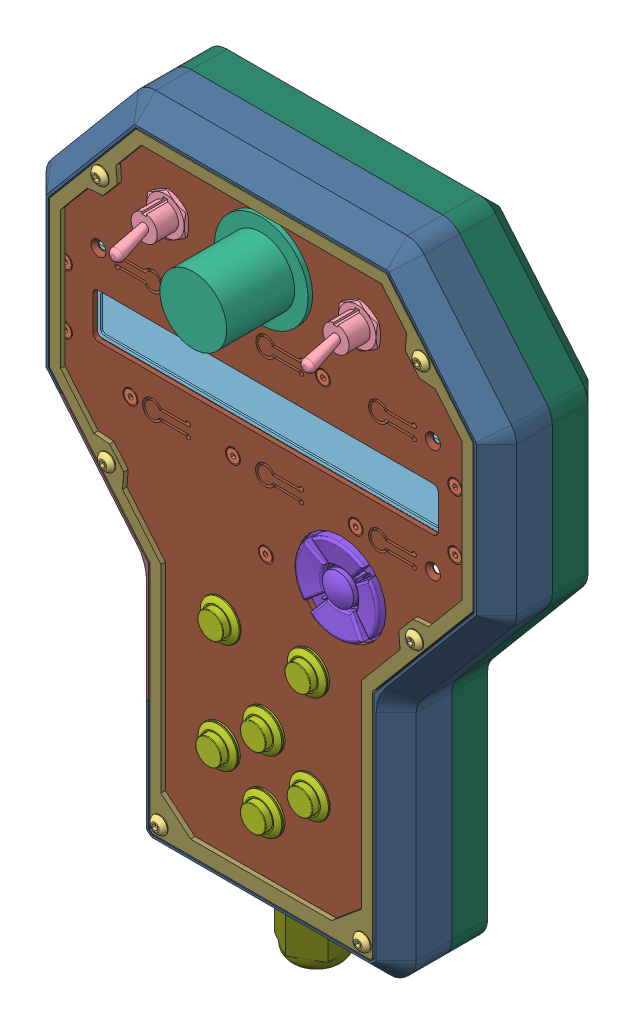
SolidWorks assembly Montagem, configuration Valor predeterminado. Lengths in mm.
Overall size (211 315 80.5).
60 component instances, 19 part files, 130 mates.
Components (placement in the parent):
- hex nut style 1 gradeab_din-3: hex nut style 1 gradeab_din [Hexagon Nut ISO 4032 - M4 - W - N] at (-95.2029 -0.5297 -15.05) x (-0.766044 -0.642788 0) z (0 0 1) size (7 8.08 3.2)
- hex nut style 1 gradeab_din-4: hex nut style 1 gradeab_din [Hexagon Nut ISO 4032 - M4 - W - N] at (42.9071 -0.5197 -15.05) x (0.766044 -0.642788 0) z (0 0 1) size (7 8.08 3.2)
- hex nut style 1 gradeab_din-5: hex nut style 1 gradeab_din [Hexagon Nut ISO 4032 - M4 - W - N] at (-69.6429 -49.9305 2.95) x (0.5 0.866025 0) z (0 0 1) size (7 8.08 3.2)
- hex nut style 1 gradeab_din-6: hex nut style 1 gradeab_din [Hexagon Nut ISO 4032 - M4 - W - N] at (33.6932 120.5695 2.95) x (0.766044 0.642788 0) z (0 0 1) size (7 8.08 3.2)
- hex nut style 1 gradeab_din-7: hex nut style 1 gradeab_din [Hexagon Nut ISO 4032 - M4 - W - N] at (17.3571 -99.7712 2.95) size (7 8.08 3.2)
- hex nut style 1 gradeab_din-8: hex nut style 1 gradeab_din [Hexagon Nut ISO 4032 - M4 - W - N] at (-85.979 120.5695 2.95) x (0.766044 -0.642788 0) z (0 0 1) size (7 8.08 3.2)
- hex nut style 1 gradeab_din-9: hex nut style 1 gradeab_din [Hexagon Nut ISO 4032 - M4 - W - N] at (-69.6429 -99.7712 2.95) size (7 8.08 3.2)
- hex nut style 1 gradeab_din-10: hex nut style 1 gradeab_din [Hexagon Nut ISO 4032 - M4 - W - N] at (45.8324 109.2141 -7.45) x (0.939693 -0.34202 0) z (0 0 -1) size (7 8.08 3.2)
- hex nut style 1 gradeab_din-11: hex nut style 1 gradeab_din [Hexagon Nut ISO 4032 - M4 - W - N] at (-71.6429 -129.7045 -7.45) x (0.5 0.866025 0) z (0 0 -1) size (7 8.08 3.2)
- hex nut style 1 gradeab_din-12: hex nut style 1 gradeab_din [Hexagon Nut ISO 4032 - M4 - W - N] at (19.3571 -129.7045 -7.45) x (1 0 0) z (0 0 -1) size (7 8.08 3.2)
- hex nut style 1 gradeab_din-13: hex nut style 1 gradeab_din [Hexagon Nut ISO 4032 - M4 - W - N] at (-98.1182 109.2141 -7.45) x (-0.939693 -0.34202 0) z (0 0 -1) size (7 8.08 3.2)
- socket countersunk head screw_din-8: socket countersunk head screw_din [DIN 7991 - M3 x 16 --- 12.8C] at (58.8311 39.2309 11.75) x (0 0 -1) z (1 0 0) size (16 5.7 5.7)
- socket countersunk head screw_din-9: socket countersunk head screw_din [DIN 7991 - M3 x 16 --- 12.8C] at (-86.7826 27.8805 11.75) x (0 0 -1) z (-0.923728 -0.383049 0) size (16 5.7 5.7)
- socket countersunk head screw_din-10: socket countersunk head screw_din [DIN 7991 - M3 x 16 --- 12.8C] at (-116.1689 65.7309 11.75) x (0 0 -1) z (-0.923728 -0.383049 0) size (16 5.7 5.7)
- socket countersunk head screw_din-11: socket countersunk head screw_din [DIN 7991 - M3 x 16 --- 12.8C] at (-0.483 78.4595 11.75) x (0 0 -1) z (0.923728 0.383049 0) size (16 5.7 5.7)
- socket countersunk head screw_din-12: socket countersunk head screw_din [DIN 7991 - M3 x 16 --- 12.8C] at (-116.1689 39.2309 11.75) x (0 0 -1) z (-0.923728 -0.383049 0) size (16 5.7 5.7)
- socket countersunk head screw_din-13: socket countersunk head screw_din [DIN 7991 - M3 x 16 --- 12.8C] at (-52.483 78.4595 11.75) x (0 0 -1) z (0.923728 0.383049 0) size (16 5.7 5.7)
- socket countersunk head screw_din-14: socket countersunk head screw_din [DIN 7991 - M3 x 16 --- 12.8C] at (58.8311 65.7309 11.75) x (0 0 -1) z (0.923728 0.383049 0) size (16 5.7 5.7)
- socket countersunk head screw_din-15: socket countersunk head screw_din [DIN 7991 - M3 x 16 --- 12.8C] at (14.2174 27.8805 11.75) x (0 0 -1) z (1 0 0) size (16 5.7 5.7)
- socket countersunk head screw_din-16: socket countersunk head screw_din [DIN 7991 - M3 x 16 --- 12.8C] at (-40.7826 27.8805 11.75) x (0 0 -1) z (0.277326 0.960776 0) size (16 5.7 5.7)
- socket countersunk head screw_din-17: socket countersunk head screw_din [DIN 7991 - M3 x 16 --- 12.8C] at (-26.2001 -3.0051 11.75) x (0 0 -1) z (-0.006263 -0.99998 0) size (16 5.7 5.7)
- hex nut style 1 gradeab_din-15: hex nut style 1 gradeab_din [Hexagon Nut ISO 4032 - M3 - W - N] at (-40.7826 27.8805 0.1586) x (0.012479 -0.999922 0) z (0 0 -1) size (5.5 6.35 2.4)
- hex nut style 1 gradeab_din-16: hex nut style 1 gradeab_din [Hexagon Nut ISO 4032 - M3 - W - N] at (-52.483 78.4595 0.1586) x (0.904381 -0.426726 0) z (0 0 -1) size (5.5 6.35 2.4)
- hex nut style 1 gradeab_din-17: hex nut style 1 gradeab_din [Hexagon Nut ISO 4032 - M3 - W - N] at (-0.483 78.4595 0.1586) x (-0.993944 0.109886 0) z (0 0 -1) size (5.5 6.35 2.4)
- hex nut style 1 gradeab_din-18: hex nut style 1 gradeab_din [Hexagon Nut ISO 4032 - M3 - W - N] at (14.2174 27.8805 0.1586) x (-0.816279 -0.577658 0) z (0 0 -1) size (5.5 6.35 2.4)
- hex nut style 1 gradeab_din-19: hex nut style 1 gradeab_din [Hexagon Nut ISO 4032 - M3 - W - N] at (-86.7826 27.8805 0.1586) x (-0.525463 -0.850817 0) z (0 0 -1) size (5.5 6.35 2.4)
- hex nut style 1 gradeab_din-20: hex nut style 1 gradeab_din [Hexagon Nut ISO 4032 - M3 - W - N] at (-116.1689 65.7309 -3.318) x (0.297598 -0.954691 0) z (0 0 -1) size (5.5 6.35 2.4)
- hex nut style 1 gradeab_din-21: hex nut style 1 gradeab_din [Hexagon Nut ISO 4032 - M3 - W - N] at (-116.1689 39.2309 -3.318) x (0.646896 0.762578 0) z (0 0 -1) size (5.5 6.35 2.4)
- hex nut style 1 gradeab_din-22: hex nut style 1 gradeab_din [Hexagon Nut ISO 4032 - M3 - W - N] at (58.8311 65.7309 -3.318) x (0.923728 0.383049 0) z (0 0 -1) size (5.5 6.35 2.4)
- hex nut style 1 gradeab_din-23: hex nut style 1 gradeab_din [Hexagon Nut ISO 4032 - M3 - W - N] at (58.8311 39.2309 -3.318) x (0.923728 0.383049 0) z (0 0 -1) size (5.5 6.35 2.4)
- hex nut style 1 gradeab_din-24: hex nut style 1 gradeab_din [Hexagon Nut ISO 4032 - M3 - W - N] at (-26.2001 -3.0051 0.1586) x (0.05846 -0.99829 0) z (0 0 -1) size (5.5 6.35 2.4)
- socket button head screw_iso-9: socket button head screw_iso [ISO 7380 - M4 x 16 --- 16N] at (45.8295 109.2085 15.95) x (0 0 -1) z (1 0 0) size (18.2 7.6 7.6)
- socket button head screw_iso-10: socket button head screw_iso [ISO 7380 - M4 x 16 --- 16N] at (-98.1153 109.2085 15.95) x (0 0 -1) z (0.767389 -0.641182 0) size (18.2 7.6 7.6)
- socket button head screw_iso-11: socket button head screw_iso [ISO 7380 - M4 x 16 --- 16N] at (-71.6429 -129.7005 15.95) x (0 0 -1) z (1 0 0) size (18.2 7.6 7.6)
- socket button head screw_iso-12: socket button head screw_iso [ISO 7380 - M4 x 16 --- 16N] at (19.3571 -129.7005 15.95) x (0 0 -1) z (1 0 0) size (18.2 7.6 7.6)
- socket button head screw_iso-14: socket button head screw_iso [ISO 7380 - M4 x 16 --- 16N] at (-95.1957 -0.5218 15.95) x (0 0 -1) z (1 0 0) size (18.2 7.6 7.6)
- socket button head screw_iso-13: socket button head screw_iso [ISO 7380 - M4 x 16 --- 16N] at (42.9099 -0.5218 15.95) x (0 0 -1) z (1 0 0) size (18.2 7.6 7.6)
- BCV3 112 103 - Controle chave geral-1: BCV3 112 103 - Controle chave geral [Default] at (-69.1429 108.0695 2.25) size (17 29 51.5)
- BCV3 112 103 - Controle chave geral-2: BCV3 112 103 - Controle chave geral [Default] at (16.8571 108.0695 2.25) size (17 29 51.5)
- LCD Display 4002-1: LCD Display 4002 [Valor predeterminado] at (-28.6689 52.4809 -3.8644) size (182 33.5 13.65)
- Botão emergencia-1: Botão emergencia [Valor predeterminado] at (-26.1429 108.0695 -28.25) x (0.351629 -0.93614 0) z (-0.93614 -0.351629 0) size (42 72.5 42)
- AV16HA-1: AV16HA [Valor predeterminado] at (-26.1429 -102.8813 -2.3) x (-0.899754 -0.436397 0) z (-0.436397 0.899754 0) size (21.5 29.33 19.15)
- AV16HA-2: AV16HA [Valor predeterminado] at (-46.1429 -38.2603 -3.25) x (0.225316 -0.974286 0) z (-0.974286 -0.225316 0) size (21.5 29.33 19.15)
- AV16HA-3: AV16HA [Valor predeterminado] at (-26.1429 -70.8635 -2.3) x (0.278036 0.960571 0) z (0.960571 -0.278036 0) size (21.5 29.33 19.15)
- AV16HA-4: AV16HA [Valor predeterminado] at (-6.1429 -86.846 -3.25) x (0.980248 0.197772 0) z (0.197772 -0.980248 0) size (21.5 29.33 19.15)
- AV16HA-5: AV16HA [Valor predeterminado] at (-46.1429 -86.846 -2.3) x (0.999797 0.02015 0) z (0.02015 -0.999797 0) size (21.5 29.33 19.15)
- AV16HA-6: AV16HA [Valor predeterminado] at (-6.1429 -38.2603 -2.3) x (-0.950101 -0.311942 0) z (-0.311942 0.950101 0) size (21.5 29.33 19.15)
- PCB-2: PCB [Valor predeterminado] at (-91.4326 8.3805 4.15) size (130.25 57.71 27.35)
- Teclas_Superiores-2: Teclas_Superiores [Valor predeterminado] at (-91.433 46.0455 4.15) size (130.25 12.75 19.2)
- TEC001 - Moldura -1: TEC001 - Moldura  [Valor predeterminado] at (-26.1429 -144.6278 -11.25) size (211 291 25)
- TEC002 - Placa Superior-1: TEC002 - Placa Superior [Valor predeterminado] at (-25.2999 1.2599 9.75) size (190 270 2)
- TEC003 - Moldura alumínio-1: TEC003 - Moldura alumínio [Valor predeterminado] at (-26.4426 -0.0902 11.75) size (190 270 2)
- TEC004 - Moldura Borracha-1: TEC004 - Moldura Borracha [Valor predeterminado] at (-26.6429 -144.6278 -11.25) size (64.1 110 25)
- TEC005 - Moldura Borracha Inferior-1: TEC005 - Moldura Borracha Inferior [Valor predeterminado] at (-26.6429 -144.6278 -11.25) size (64.1 110 25)
- TEC006 - Placa Inferior-1: TEC006 - Placa Inferior [Valor predeterminado] at (-25.2999 1.2599 -34.75) size (190 270 1.5) (hidden)
- TEC007 - Moldura  Inferior-1: TEC007 - Moldura  Inferior [Valor predeterminado] at (-26.1429 -144.6278 -11.25) size (211 291 25)
- Prensa cabo-1: Prensa cabo [Valor predeterminado] at (-26.1429 -154.9305 -11.0191) x (0.5 0 0.866025) z (0 -1 0) size (27.2 31.41 34)
- TEC008 - Pino-1: TEC008 - Pino [Valor predeterminado] at (-127.6429 32.3003 0.75) x (0.794362 -0.607445 0) z (0.607445 0.794362 0) size (4 25 4)
- TEC008 - Pino-2: TEC008 - Pino [Valor predeterminado] at (-80.1429 -114.1997 -24.25) x (0.610836 -0.791757 0) z (-0.791757 -0.610836 0) size (4 25 4)
- placa inferior-1: placa inferior [Valor predeterminado] at (-18.5596 4.7575 -324.8091) x (-1 0 0) z (0 0 -1) size (146 57.5 4) (hidden)
Mates (geometry in assembly coordinates):
- Coincidente2: coincident: plane of TEC001 - Moldura -1 through (-26.1429 -144.6278 13.75) normal (0 0 1); plane of Botão emergencia-1 through (-33.5271 127.7285 13.75) normal (0 0 1)
- Coincidente24: coincident: plane of TEC001 - Moldura -1 through (-26.1429 -144.6278 9.75) normal (0 0 1); plane of TEC002 - Placa Superior-1 through (-25.2999 1.2599 9.75) normal (0 0 -1)
- Coincidente35: coincident: plane of TEC001 - Moldura -1 through (-49.8107 -84.1997 -11.25) normal (0 1 0); plane of TEC004 - Moldura Borracha-1 through (-50.3107 -84.1997 -11.25) normal (0 -1 0)
- Coincidente36: coincident: plane of TEC002 - Placa Superior-1 through (-25.2999 1.2599 9.75) normal (0 0 -1); plane of TEC004 - Moldura Borracha-1 through (-26.6429 -144.6278 9.75) normal (0 0 1)
- Concêntrico6: concentric: cylinder of AV16HA-1 through (-26.1429 -102.8813 -2.3) axis (0 0 1) radius 7.95; cylinder of TEC002 - Placa Superior-1 through (-26.1429 -102.8813 9.749) axis (0 0 1) radius 8
- Tangente1: tangent: plane of TEC002 - Placa Superior-1 through (-25.2999 1.2599 11.75) normal (0 0 1); face of AV16HA-1
- Concêntrico9: concentric: cylinder of AV16HA-4 through (-6.1429 -86.846 -3.25) axis (0 0 1) radius 7.95; cylinder of TEC002 - Placa Superior-1 through (-6.1429 -86.846 9.749) axis (0 0 1) radius 8
- Concêntrico10: concentric: cylinder of AV16HA-3 through (-26.1429 -70.8635 -2.3) axis (0 0 1) radius 7.95; cylinder of TEC002 - Placa Superior-1 through (-26.1429 -70.8635 9.749) axis (0 0 1) radius 8
- Tangente2: tangent: plane of TEC002 - Placa Superior-1 through (-25.2999 1.2599 11.75) normal (0 0 1); face of AV16HA-5
- Tangente3: tangent: plane of TEC002 - Placa Superior-1 through (-25.2999 1.2599 11.75) normal (0 0 1); face of AV16HA-6
- Tangente4: tangent: plane of TEC002 - Placa Superior-1 through (-25.2999 1.2599 11.75) normal (0 0 1); face of AV16HA-4
- Tangente5: tangent: plane of TEC002 - Placa Superior-1 through (-25.2999 1.2599 11.75) normal (0 0 1); face of AV16HA-2
- Tangente6: tangent: plane of TEC002 - Placa Superior-1 through (-25.2999 1.2599 11.75) normal (0 0 1); face of AV16HA-3
- Concêntrico12: concentric: cylinder of Botão emergencia-1 through (-26.1429 108.0695 -50.7451) axis (0 0 -1) radius 15; cylinder of TEC002 - Placa Superior-1 through (-26.1429 108.0695 9.749) axis (0 0 1) radius 11.25
- Concêntrico13: concentric: cylinder of BCV3 112 103 - Controle chave geral-1 through (-69.1429 108.0695 23.25) axis (0 0 -1) radius 5.85; cylinder of TEC002 - Placa Superior-1 through (-69.1429 108.0695 9.749) axis (0 0 1) radius 6
- Concêntrico15: concentric: cylinder of BCV3 112 103 - Controle chave geral-2 through (16.8571 108.0695 23.25) axis (0 0 -1) radius 5.85; cylinder of TEC002 - Placa Superior-1 through (16.8571 108.0695 9.749) axis (0 0 1) radius 6
- Coincidente38: coincident: plane of BCV3 112 103 - Controle chave geral-1 through (-69.1429 117.8845 11.75) normal (0 0 -1); plane of TEC002 - Placa Superior-1 through (-25.2999 1.2599 11.75) normal (0 0 1)
- Coincidente39: coincident: plane of BCV3 112 103 - Controle chave geral-2 through (16.8571 117.8845 11.75) normal (0 0 -1); plane of TEC002 - Placa Superior-1 through (-25.2999 1.2599 11.75) normal (0 0 1)
- Coincidente40: coincident: plane of TEC001 - Moldura -1 through (-39.9429 -142.4305 -3.2826) normal (0.5 0 -0.866025); plane of Prensa cabo-1 through (-39.7429 -142.4305 -3.1671) normal (-0.5 0 0.866025)
- Coincidente41: coincident: plane of TEC001 - Moldura -1 through (-26.1429 -142.4305 4.6849) normal (-0.5 0 -0.866025); plane of Prensa cabo-1 through (-26.1429 -142.4305 4.6849) normal (0.5 0 0.866025)
- Coincidente42: coincident: plane of TEC001 - Moldura -1 through (-26.1429 -142.4305 -11.25) normal (0 1 0); plane of Prensa cabo-1 through (-26.1429 -142.4305 -11.0191) normal (0 -1 0)
- Distância9: distance = 0.5 mm: plane of TEC002 - Placa Superior-1 through (-121.1429 88.7866 11.75) normal (-1 0 0); plane of TEC001 - Moldura -1 through (-121.6429 88.9571 9.75) normal (1 0 0)
- Distância10: distance = 0.5 mm: plane of TEC002 - Placa Superior-1 through (30.0211 135.0695 11.75) normal (0 1 0); plane of TEC001 - Moldura -1 through (30.2446 135.5695 9.75) normal (0 -1 0)
- Coincidente49: coincident: plane of TEC002 - Placa Superior-1 through (-25.2999 1.2599 11.75) normal (0 0 1); plane of TEC003 - Moldura alumínio-1 through (-26.4426 -0.0902 11.75) normal (0 0 -1)
- Coincidente50: coincident: plane of TEC002 - Placa Superior-1 through (-121.1429 88.7866 11.75) normal (-1 0 0); plane of TEC003 - Moldura alumínio-1 through (-121.1429 88.7866 13.75) normal (-1 0 0)
- Coincidente51: coincident: plane of TEC002 - Placa Superior-1 through (-74.8228 -134.9305 11.75) normal (0 -1 0); plane of TEC003 - Moldura alumínio-1 through (-74.8228 -134.9305 13.75) normal (0 -1 0)
- Coincidente52: coincident: plane of TEC001 - Moldura -1 through (-86.6429 -144.6278 13.75) normal (-1 0 0); plane of TEC004 - Moldura Borracha-1 through (-86.6429 -144.6278 13.75) normal (-1 0 0)
- Coincidente53: coincident: plane of TEC001 - Moldura -1 through (-26.1429 145.5695 13.75) normal (0 1 0); plane of TEC007 - Moldura  Inferior-1 through (-26.1429 145.5695 13.75) normal (0 1 0)
- Coincidente54: coincident: plane of TEC001 - Moldura -1 through (-204.8631 5.3363 13.75) normal (-0.766044 0.642788 0); plane of TEC007 - Moldura  Inferior-1 through (-204.8631 5.3363 13.75) normal (-0.766044 0.642788 0)
- Coincidente55: coincident: plane of TEC001 - Moldura -1 through (152.5774 5.3363 13.75) normal (0.766044 0.642788 0); plane of TEC007 - Moldura  Inferior-1 through (152.5774 5.3363 13.75) normal (0.766044 0.642788 0)
- Coincidente56: coincident: plane of TEC006 - Placa Inferior-1 through (-25.2999 1.2599 -33.25) normal (0 0 1); plane of TEC007 - Moldura  Inferior-1 through (-26.1429 -144.6278 -33.25) normal (0 0 -1)
- Distância11: distance = 0.5 mm: plane of TEC006 - Placa Inferior-1 through (30.0211 135.0695 -33.25) normal (0 1 0); plane of TEC007 - Moldura  Inferior-1 through (30.2446 135.5695 -33.25) normal (0 -1 0)
- Distância12: distance = 0.5 mm: plane of TEC006 - Placa Inferior-1 through (-121.1429 88.7866 -33.25) normal (-1 0 0); plane of TEC007 - Moldura  Inferior-1 through (-121.6429 88.9571 -33.25) normal (1 0 0)
- Coincidente57: coincident: plane of TEC007 - Moldura  Inferior-1 through (-26.1429 -144.6278 -11.25) normal (0 0 1); plane of TEC005 - Moldura Borracha Inferior-1 through (-26.6429 -144.6278 -11.25) normal (0 0 1)
- Coincidente58: coincident: plane of TEC007 - Moldura  Inferior-1 through (-49.8107 -84.1997 -11.25) normal (0 1 0); plane of TEC005 - Moldura Borracha Inferior-1 through (-50.3107 -84.1997 -11.25) normal (0 -1 0)
- Coincidente59: coincident: plane of TEC007 - Moldura  Inferior-1 through (-7.3536 -128.8618 13.75) normal (-0.766044 -0.642788 0); plane of TEC005 - Moldura Borracha Inferior-1 through (-7.5602 -128.6156 13.75) normal (-0.766044 -0.642788 0)
- Paralelo2: parallel: plane of TEC001 - Moldura -1 through (30.2446 135.5695 9.75) normal (0 -1 0); plane of BCV3 112 103 - Controle chave geral-1 through (-77.1429 122.5695 10.25) normal (0 1 0)
- Paralelo3: parallel: plane of TEC001 - Moldura -1 through (30.2446 135.5695 9.75) normal (0 -1 0); plane of BCV3 112 103 - Controle chave geral-2 through (8.8571 122.5695 10.25) normal (0 1 0)
- Concêntrico17: concentric: cylinder of TEC001 - Moldura -1 through (33.6932 120.5695 -11.25) axis (0 0 1) radius 2.2; cylinder of hex nut style 1 gradeab_din-6 through (33.6932 120.5695 -0.25) axis (0 0 1) radius 1.65
- Concêntrico18: concentric: cylinder of TEC001 - Moldura -1 through (-85.979 120.5695 -11.25) axis (0 0 1) radius 2.2; cylinder of hex nut style 1 gradeab_din-8 through (-85.979 120.5695 -0.25) axis (0 0 1) radius 1.65
- Paralelo4: parallel: plane of TEC001 - Moldura -1 through (-90.1865 121.3114 -0.25) normal (0.939693 0.34202 0); plane of hex nut style 1 gradeab_din-8 through (-89.9591 121.2713 -0.25) normal (-0.939693 -0.34202 0)
- Paralelo5: parallel: plane of TEC001 - Moldura -1 through (-87.4403 124.5843 -0.25) normal (0.766044 -0.642788 0); plane of hex nut style 1 gradeab_din-8 through (-87.3613 124.3672 -0.25) normal (-0.766044 0.642788 0)
- Coincidente67: coincident: plane of TEC001 - Moldura -1 through (-26.1429 -144.6278 -0.25) normal (0 0 1); plane of hex nut style 1 gradeab_din-8 through (-83.3812 123.6655 -0.25) normal (0 0 -1)
- Paralelo6: parallel: plane of TEC001 - Moldura -1 through (30.947 123.8424 -0.25) normal (0.939693 -0.34202 0); plane of hex nut style 1 gradeab_din-6 through (31.0955 123.6655 -0.25) normal (-0.939693 0.34202 0)
- Coincidente69: coincident: plane of TEC001 - Moldura -1 through (-26.1429 -144.6278 -0.25) normal (0 0 1); plane of hex nut style 1 gradeab_din-6 through (31.0955 123.6655 -0.25) normal (0 0 -1)
- Concêntrico21: concentric: cylinder of TEC004 - Moldura Borracha-1 through (-69.6429 -49.9305 -11.25) axis (0 0 1) radius 2.2; cylinder of hex nut style 1 gradeab_din-5 through (-69.6429 -49.9305 -0.25) axis (0 0 1) radius 1.65
- Paralelo9: parallel: plane of TEC004 - Moldura Borracha-1 through (-65.9429 -52.0667 -0.25) normal (-1 0 0); plane of hex nut style 1 gradeab_din-5 through (-73.1429 -47.9097 -0.25) normal (-1 0 0)
- Coincidente76: coincident: plane of TEC004 - Moldura Borracha-1 through (-26.6429 -144.6278 -0.25) normal (0 0 1); plane of hex nut style 1 gradeab_din-5 through (-73.1429 -47.9097 -0.25) normal (0 0 -1)
- Concêntrico22: concentric: cylinder of TEC001 - Moldura -1 through (17.3571 -99.7712 -11.25) axis (0 0 1) radius 2.2; cylinder of hex nut style 1 gradeab_din-7 through (17.3571 -99.7712 -0.25) axis (0 0 1) radius 1.65
- Paralelo10: parallel: plane of TEC001 - Moldura -1 through (21.0571 -101.9074 -0.25) normal (-1 0 0); plane of hex nut style 1 gradeab_din-7 through (13.8571 -97.7505 -0.25) normal (-1 0 0)
- Coincidente78: coincident: plane of TEC001 - Moldura -1 through (-26.1429 -144.6278 -0.25) normal (0 0 1); plane of hex nut style 1 gradeab_din-7 through (17.3571 -95.7298 -0.25) normal (0 0 -1)
- Concêntrico23: concentric: cylinder of TEC001 - Moldura -1 through (-69.6429 -99.7712 -11.25) axis (0 0 1) radius 2.2; cylinder of hex nut style 1 gradeab_din-9 through (-69.6429 -99.7712 -0.25) axis (0 0 1) radius 1.65
- Paralelo11: parallel: plane of TEC001 - Moldura -1 through (-65.9429 -101.9074 -0.25) normal (-1 0 0); plane of hex nut style 1 gradeab_din-9 through (-73.1429 -97.7505 -0.25) normal (-1 0 0)
- Coincidente80: coincident: plane of TEC001 - Moldura -1 through (-26.1429 -144.6278 -0.25) normal (0 0 1); plane of hex nut style 1 gradeab_din-9 through (-69.6429 -95.7298 -0.25) normal (0 0 -1)
- Concêntrico24: concentric: cylinder of TEC001 - Moldura -1 through (-71.6429 -129.7045 -11.25) axis (0 0 1) radius 2.2; cylinder of hex nut style 1 gradeab_din-11 through (-71.6429 -129.7045 -4.25) axis (0 0 -1) radius 1.65
- Paralelo12: parallel: plane of TEC001 - Moldura -1 through (-67.9429 -127.5683 3.75) normal (-0.5 -0.866025 0); plane of hex nut style 1 gradeab_din-11 through (-68.1429 -127.6838 -4.25) normal (0.5 0.866025 0)
- Concêntrico25: concentric: cylinder of TEC001 - Moldura -1 through (19.3571 -129.7045 -11.25) axis (0 0 1) radius 2.2; cylinder of hex nut style 1 gradeab_din-12 through (19.3571 -129.7045 -4.25) axis (0 0 -1) radius 1.65
- Paralelo13: parallel: plane of TEC001 - Moldura -1 through (15.6571 -131.8407 3.75) normal (1 0 0); plane of hex nut style 1 gradeab_din-12 through (22.8571 -131.7252 -4.25) normal (1 0 0)
- Concêntrico27: concentric: cylinder of TEC001 - Moldura -1 through (45.8324 109.2141 -11.25) axis (0 0 1) radius 2.2; cylinder of hex nut style 1 gradeab_din-10 through (45.8324 109.2141 -4.25) axis (0 0 -1) radius 1.65
- Paralelo14: parallel: plane of TEC001 - Moldura -1 through (43.0861 112.487 3.75) normal (0.173648 -0.984808 0); plane of hex nut style 1 gradeab_din-10 through (48.4302 106.1182 -4.25) normal (0.173648 -0.984808 0)
- Concêntrico28: concentric: cylinder of TEC001 - Moldura -1 through (-98.1182 109.2141 -11.25) axis (0 0 1) radius 2.2; cylinder of hex nut style 1 gradeab_din-13 through (-98.1182 109.2141 -4.25) axis (0 0 -1) radius 1.65
- Paralelo15: parallel: plane of TEC001 - Moldura -1 through (-99.5794 113.2289 3.75) normal (-0.173648 -0.984808 0); plane of hex nut style 1 gradeab_din-13 through (-96.7359 105.4164 -4.25) normal (-0.173648 -0.984808 0)
- Coincidente89: coincident: plane of TEC001 - Moldura -1 through (-26.1429 -144.6278 -11.25) normal (0 0 -1); plane of TEC007 - Moldura  Inferior-1 through (-26.1429 -144.6278 -11.25) normal (0 0 1)
- Concêntrico53: concentric: cone of TEC002 - Placa Superior-1 through (14.2174 27.8805 11.75) axis (0 0 -1); cylinder of socket countersunk head screw_din-15 through (14.2174 27.8805 11.75) axis (0 0 1) radius 1.5
- Concêntrico54: concentric: cone of TEC002 - Placa Superior-1 through (58.8311 39.2309 11.75) axis (0 0 -1); cylinder of socket countersunk head screw_din-8 through (58.8311 39.2309 11.75) axis (0 0 1) radius 1.5
- Concêntrico55: concentric: cone of TEC002 - Placa Superior-1 through (58.8311 65.7309 11.75) axis (0 0 -1); cylinder of socket countersunk head screw_din-14 through (58.8311 65.7309 11.75) axis (0 0 1) radius 1.5
- Concêntrico56: concentric: cone of TEC002 - Placa Superior-1 through (-0.483 78.4595 11.75) axis (0 0 -1); cylinder of socket countersunk head screw_din-11 through (-0.483 78.4595 11.75) axis (0 0 1) radius 1.5
- Concêntrico57: concentric: cone of TEC002 - Placa Superior-1 through (-52.483 78.4595 11.75) axis (0 0 -1); cylinder of socket countersunk head screw_din-13 through (-52.483 78.4595 11.75) axis (0 0 1) radius 1.5
- Concêntrico58: concentric: circle of TEC002 - Placa Superior-1; cylinder of socket countersunk head screw_din-10 through (-116.1689 65.7309 11.75) axis (0 0 1) radius 1.5
- Concêntrico59: concentric: cylinder of socket countersunk head screw_din-12 through (-116.1689 39.2309 11.75) axis (0 0 1) radius 1.5; circle of TEC002 - Placa Superior-1
- Concêntrico60: concentric: cone of TEC002 - Placa Superior-1 through (-86.7826 27.8805 11.75) axis (0 0 -1); cylinder of socket countersunk head screw_din-9 through (-86.7826 27.8805 11.75) axis (0 0 1) radius 1.5
- Coincidente105: coincident: plane of TEC002 - Placa Superior-1 through (-25.2999 1.2599 11.75) normal (0 0 1); plane of socket countersunk head screw_din-15 through (14.2174 27.8805 11.75) normal (0 0 1)
- Coincidente106: coincident: plane of TEC002 - Placa Superior-1 through (-25.2999 1.2599 11.75) normal (0 0 1); plane of socket countersunk head screw_din-8 through (58.8311 39.2309 11.75) normal (0 0 1)
- Coincidente107: coincident: plane of TEC002 - Placa Superior-1 through (-25.2999 1.2599 11.75) normal (0 0 1); line of socket countersunk head screw_din-14 through (58.1215 64.8054 11.75) axis (-0.383049 0.923728 0)
- Coincidente108: coincident: plane of TEC002 - Placa Superior-1 through (-25.2999 1.2599 11.75) normal (0 0 1); plane of socket countersunk head screw_din-11 through (-0.483 78.4595 11.75) normal (0 0 1)
- Coincidente109: coincident: plane of TEC002 - Placa Superior-1 through (-25.2999 1.2599 11.75) normal (0 0 1); plane of socket countersunk head screw_din-10 through (-116.1689 65.7309 11.75) normal (0 0 1)
- Coincidente110: coincident: plane of TEC002 - Placa Superior-1 through (-25.2999 1.2599 11.75) normal (0 0 1); circle of socket countersunk head screw_din-13
- Coincidente111: coincident: plane of TEC002 - Placa Superior-1 through (-25.2999 1.2599 11.75) normal (0 0 1); plane of socket countersunk head screw_din-9 through (-86.7826 27.8805 11.75) normal (0 0 1)
- Coincidente112: coincident: plane of TEC002 - Placa Superior-1 through (-25.2999 1.2599 11.75) normal (0 0 1); plane of socket countersunk head screw_din-12 through (-116.1689 39.2309 11.75) normal (0 0 1)
- Concêntrico61: concentric: cone of TEC002 - Placa Superior-1 through (-40.7826 27.8805 11.75) axis (0 0 -1); cylinder of socket countersunk head screw_din-16 through (-40.7826 27.8805 11.75) axis (0 0 1) radius 1.5
- Coincidente113: coincident: plane of TEC002 - Placa Superior-1 through (-25.2999 1.2599 11.75) normal (0 0 1); plane of socket countersunk head screw_din-16 through (-40.7826 27.8805 11.75) normal (0 0 1)
- Coincidente114: coincident: plane of TEC002 - Placa Superior-1 through (-25.2999 1.2599 11.75) normal (0 0 1); plane of socket countersunk head screw_din-17 through (-26.2001 -3.0051 11.75) normal (0 0 1)
- Concêntrico63: concentric: cone of socket countersunk head screw_din-13 through (-52.483 78.4595 -4.25) axis (0 0 -1); cylinder of hex nut style 1 gradeab_din-16 through (-52.483 78.4595 25.1961) axis (0 0 -1) radius 1.5
- Concêntrico64: concentric: cylinder of socket countersunk head screw_din-11 through (-0.483 78.4595 11.75) axis (0 0 1) radius 1.5; cylinder of hex nut style 1 gradeab_din-17 through (-0.483 78.4595 25.1961) axis (0 0 -1) radius 1.5
- Concêntrico65: concentric: cylinder of socket countersunk head screw_din-15 through (14.2174 27.8805 11.75) axis (0 0 1) radius 1.5; cylinder of hex nut style 1 gradeab_din-18 through (14.2174 27.8805 25.1961) axis (0 0 -1) radius 1.5
- Concêntrico66: concentric: cylinder of socket countersunk head screw_din-9 through (-86.7826 27.8805 11.75) axis (0 0 1) radius 1.5; cylinder of hex nut style 1 gradeab_din-19 through (-86.7826 27.8805 25.1961) axis (0 0 -1) radius 1.5
- Concêntrico67: concentric: cylinder of socket countersunk head screw_din-10 through (-116.1689 65.7309 11.75) axis (0 0 1) radius 1.5; cylinder of hex nut style 1 gradeab_din-20 through (-116.1689 65.7309 21.7195) axis (0 0 -1) radius 1.5
- Concêntrico68: concentric: cylinder of socket countersunk head screw_din-12 through (-116.1689 39.2309 11.75) axis (0 0 1) radius 1.5; cylinder of hex nut style 1 gradeab_din-21 through (-116.1689 39.2309 21.7195) axis (0 0 -1) radius 1.5
- Concêntrico69: concentric: cylinder of socket countersunk head screw_din-14 through (58.8311 65.7309 11.75) axis (0 0 1) radius 1.5; cylinder of hex nut style 1 gradeab_din-22 through (58.8311 65.7309 21.7195) axis (0 0 -1) radius 1.5
- Concêntrico70: concentric: cylinder of socket countersunk head screw_din-8 through (58.8311 39.2309 11.75) axis (0 0 1) radius 1.5; cylinder of hex nut style 1 gradeab_din-23 through (58.8311 39.2309 21.7195) axis (0 0 -1) radius 1.5
- Concêntrico71: concentric: cylinder of socket countersunk head screw_din-17 through (-26.2001 -3.0051 11.75) axis (0 0 1) radius 1.5; cylinder of hex nut style 1 gradeab_din-24 through (-26.2001 -3.0051 2.5586) axis (0 0 -1) radius 1.25
- Concêntrico72: concentric: cylinder of TEC003 - Moldura alumínio-1 through (45.8295 109.2085 11.749) axis (0 0 1) radius 2.1; cylinder of socket button head screw_iso-9 through (45.8295 109.2085 15.95) axis (0 0 1) radius 3.8
- Coincidente124: coincident: plane of TEC003 - Moldura alumínio-1 through (-26.4426 -0.0902 13.75) normal (0 0 1); plane of socket button head screw_iso-9 through (45.8295 111.2085 13.75) normal (0 0 -1)
- Concêntrico73: concentric: cylinder of TEC003 - Moldura alumínio-1 through (-98.1153 109.2085 11.749) axis (0 0 1) radius 2.1; cylinder of socket button head screw_iso-10 through (-98.1153 109.2085 15.95) axis (0 0 1) radius 3.8
- Coincidente125: coincident: plane of TEC003 - Moldura alumínio-1 through (-26.4426 -0.0902 13.75) normal (0 0 1); plane of socket button head screw_iso-10 through (-96.8329 110.7433 13.75) normal (0 0 -1)
- Concêntrico74: concentric: cylinder of TEC003 - Moldura alumínio-1 through (-71.6429 -129.7005 11.749) axis (0 0 1) radius 2.1; cylinder of socket button head screw_iso-11 through (-71.6429 -129.7005 15.95) axis (0 0 1) radius 3.8
- Coincidente126: coincident: plane of TEC003 - Moldura alumínio-1 through (-26.4426 -0.0902 13.75) normal (0 0 1); plane of socket button head screw_iso-11 through (-71.6429 -127.7005 13.75) normal (0 0 -1)
- Concêntrico75: concentric: cylinder of TEC003 - Moldura alumínio-1 through (19.3571 -129.7005 11.749) axis (0 0 1) radius 2.1; cylinder of socket button head screw_iso-12 through (19.3571 -129.7005 15.95) axis (0 0 1) radius 3.8
- Coincidente127: coincident: plane of TEC003 - Moldura alumínio-1 through (-26.4426 -0.0902 13.75) normal (0 0 1); plane of socket button head screw_iso-12 through (19.3571 -127.7005 13.75) normal (0 0 -1)
- Concêntrico76: concentric: cylinder of socket countersunk head screw_din-16 through (-40.7826 27.8805 11.75) axis (0 0 1) radius 1.5; cylinder of hex nut style 1 gradeab_din-15 through (-40.7826 27.8805 2.5586) axis (0 0 -1) radius 1.25
- Concêntrico77: concentric: cylinder of TEC007 - Moldura  Inferior-1 through (-127.6429 32.3003 -24.25) axis (0 0 1) radius 2.2; cylinder of TEC008 - Pino-1 through (-127.6429 32.3003 -24.25) axis (0 0 1) radius 2
- Coincidente138: coincident: plane of TEC007 - Moldura  Inferior-1 through (-127.6429 32.3003 -24.25) normal (0 0 1); plane of TEC008 - Pino-1 through (-127.6429 32.3003 -24.25) normal (0 0 -1)
- Concêntrico78: concentric: cylinder of TEC007 - Moldura  Inferior-1 through (-80.1429 -114.1997 -24.25) axis (0 0 1) radius 2.2; cylinder of TEC008 - Pino-2 through (-80.1429 -114.1997 0.75) axis (0 0 -1) radius 2
- Coincidente139: coincident: plane of TEC007 - Moldura  Inferior-1 through (-80.1429 -114.1997 -24.25) normal (0 0 1); plane of TEC008 - Pino-2 through (-80.1429 -114.1997 -24.25) normal (0 0 -1)
- Coincidente140: coincident: plane of TEC003 - Moldura alumínio-1 through (-26.4426 -0.0902 13.75) normal (0 0 1); plane of socket button head screw_iso-14 through (-95.1957 1.4782 13.75) normal (0 0 -1)
- Concêntrico80: concentric: cylinder of TEC003 - Moldura alumínio-1 through (-95.1957 -0.5218 11.749) axis (0 0 1) radius 2.1; cylinder of socket button head screw_iso-14 through (-95.1957 -0.5218 15.95) axis (0 0 1) radius 2
- Coincidente141: coincident: plane of TEC003 - Moldura alumínio-1 through (-26.4426 -0.0902 13.75) normal (0 0 1); plane of socket button head screw_iso-13 through (42.9099 1.4782 13.75) normal (0 0 -1)
- Concêntrico82: concentric: cylinder of TEC003 - Moldura alumínio-1 through (42.9099 -0.5218 11.749) axis (0 0 1) radius 2.1; cylinder of socket button head screw_iso-13 through (42.9099 -0.5218 15.95) axis (0 0 1) radius 2
- Concêntrico83: concentric: cylinder of hex nut style 1 gradeab_din-3 through (-95.2029 -0.5297 -18.25) axis (0 0 1) radius 1.65; cylinder of TEC005 - Moldura Borracha Inferior-1 through (-95.2029 -0.5297 -11.249) axis (0 0 -1) radius 2.1
- Paralelo16: parallel: plane of hex nut style 1 gradeab_din-3 through (-96.5852 -4.3274 -18.25) normal (-0.766044 -0.642788 0); plane of TEC005 - Moldura Borracha Inferior-1 through (-90.9954 0.2122 -26.25) normal (-0.766044 -0.642788 0)
- Coincidente143: coincident: plane of hex nut style 1 gradeab_din-3 through (-92.6051 -3.6256 -18.25) normal (0 0 -1); line of TEC005 - Moldura Borracha Inferior-1 through (-93.7417 3.485 -18.25) axis (0.642788 -0.766044 0)
- Concêntrico84: concentric: cylinder of hex nut style 1 gradeab_din-4 through (42.9071 -0.5197 -18.25) axis (0 0 1) radius 1.65; cylinder of TEC007 - Moldura  Inferior-1 through (42.9071 -0.5197 -36.251) axis (0 0 1) radius 2.2
- Paralelo17: parallel: plane of hex nut style 1 gradeab_din-4 through (46.8872 -1.2215 -18.25) normal (0.766044 -0.642788 0); plane of TEC007 - Moldura  Inferior-1 through (41.4459 3.495 -26.25) normal (0.766044 -0.642788 0)
- Coincidente145: coincident: plane of hex nut style 1 gradeab_din-4 through (45.5049 2.5762 -18.25) normal (0 0 -1); line of TEC007 - Moldura  Inferior-1 through (38.6996 0.2222 -18.25) axis (0.642788 0.766044 0)
- Coincidente146: coincident: plane of hex nut style 1 gradeab_din-10 through (44.4501 105.4164 -4.25) normal (0 0 1); line of TEC001 - Moldura -1 through (43.0861 112.487 -4.25) axis (-0.34202 -0.939693 0)
- Coincidente147: coincident: plane of hex nut style 1 gradeab_din-13 through (-99.5004 113.0119 -4.25) normal (0 0 1); line of TEC001 - Moldura -1 through (-99.5794 113.2289 -4.25) axis (-0.642788 -0.766044 0)
- Coincidente148: coincident: plane of hex nut style 1 gradeab_din-12 through (19.3571 -133.7459 -4.25) normal (0 0 1); moEndPointRef_w of TEC001 - Moldura -1
- Coincidente149: coincident: plane of hex nut style 1 gradeab_din-11 through (-68.1429 -131.7252 -4.25) normal (0 0 1); line of TEC001 - Moldura -1 through (-71.6429 -125.4321 -4.25) axis (-0.866025 -0.5 0)
- Distância13: distance = 5.6 mm: plane of PCB-2 through (-64.1256 -24.1545 4.15) normal (0 0 1); plane of TEC002 - Placa Superior-1 through (-25.2999 1.2599 9.75) normal (0 0 -1)
- Concêntrico86: concentric: circle of PCB-2; cylinder of TEC002 - Placa Superior-1 through (7.7564 1.0695 9.749) axis (0 0 1) radius 20
- Paralelo18: parallel: plane of PCB-2 through (38.6944 33.3805 2.5586) normal (1 0 0); plane of TEC002 - Placa Superior-1 through (68.8571 88.7866 11.75) normal (1 0 0)
- Coincidente153: coincident: plane of PCB-2 through (-64.1256 -24.1545 4.15) normal (0 0 1); plane of Teclas_Superiores-2 through (-91.433 71.9185 4.15) normal (0 0 1)
- Coincidente154: coincident: plane of PCB-2 through (-91.5596 8.3805 2.5586) normal (-1 0 0); plane of Teclas_Superiores-2 through (-91.56 72.0455 2.5586) normal (-1 0 0)
- Concêntrico87: concentric: cylinder of AV16HA-5 through (-46.1429 -86.846 -2.3) axis (0 0 1) radius 7.95; cylinder of TEC002 - Placa Superior-1 through (-46.1429 -86.846 9.749) axis (0 0 1) radius 8
- Concêntrico88: concentric: cylinder of AV16HA-6 through (-6.1429 -38.2603 -2.3) axis (0 0 1) radius 7.95; cylinder of TEC002 - Placa Superior-1 through (-6.1429 -38.2603 9.749) axis (0 0 1) radius 8
- Concêntrico89: concentric: cylinder of AV16HA-2 through (-46.1429 -38.2603 -3.25) axis (0 0 1) radius 6.25; cylinder of TEC002 - Placa Superior-1 through (-46.1429 -38.2603 9.749) axis (0 0 1) radius 8
- Concêntrico90: concentric: cylinder of Teclas_Superiores-2 through (-26.1329 77.7395 7.958) axis (0 0 -1) radius 1.75; cylinder of TEC002 - Placa Superior-1 through (-26.1329 77.7395 1.75) axis (0 0 1) radius 3.5
- Coincidente156: coincident: plane of PCB-2 through (-91.5596 8.3805 2.5586) normal (-1 0 0); plane of placa inferior-1 through (-91.5596 8.5075 -326.8091) normal (-1 0 0)
- Coincidente157: coincident: plane of PCB-2 through (-91.4326 33.5075 2.5586) normal (0 1 0); plane of placa inferior-1 through (54.4404 33.5075 -326.8091) normal (0 1 0)
- Paralelo19: parallel: plane of PCB-2 through (-64.1256 -24.1545 2.5586) normal (0 0 -1); plane of placa inferior-1 through (-18.5596 4.7575 -326.8091) normal (0 0 -1)
